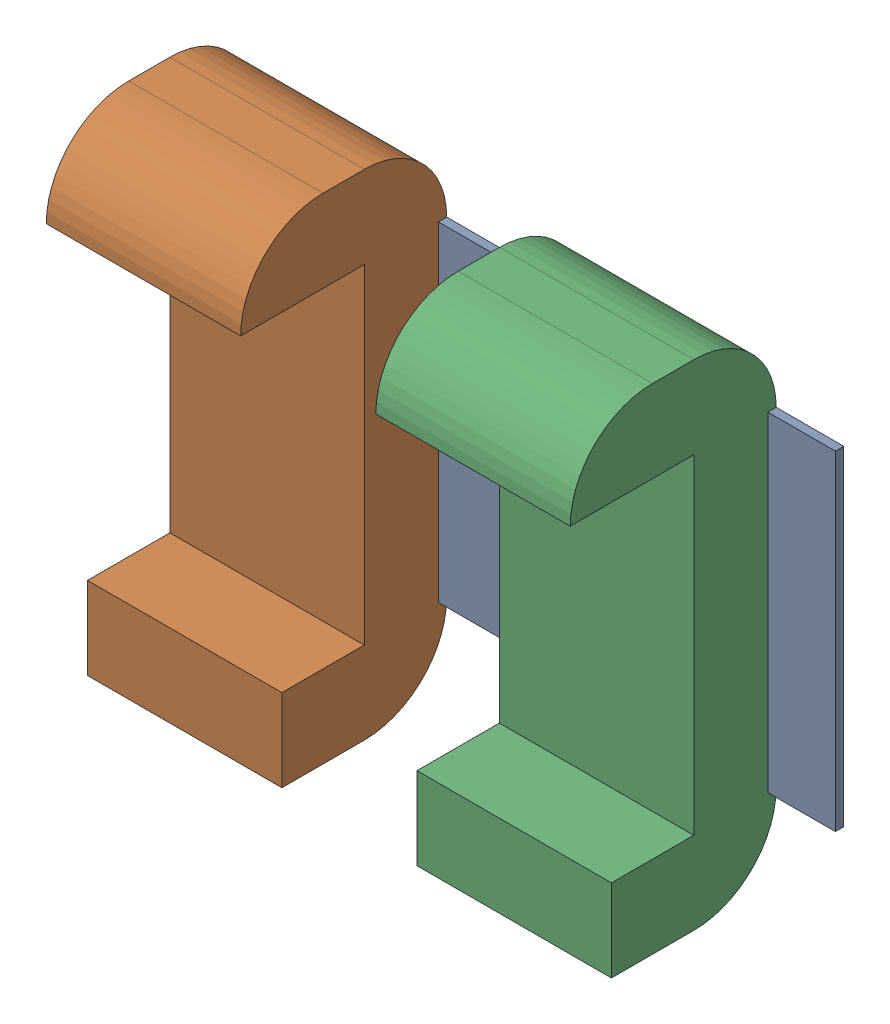
SolidWorks assembly JP1, configuration Predeterminado. Lengths in mm.
Overall size (2 1.5 0.63).
4 component instances, 3 part files, 0 mates.
Components (placement in the parent):
- Open CASCADE STEP translator 6.8 1.11.1-1: Open CASCADE STEP translator 6.8 1.11.1 [Predeterminado] at origin size (2 1.5 0.63)
  - Body_1_4-1: Body_1_4 [Predeterminado] at origin size (2 1 0.03)
  - Pin_1_3-1: Pin_1_3 [Predeterminado] x (0 1 0) z (0 0 1) size (1.5 0.59 0.63)
  - Pin_2_3-1: Pin_2_3 [Predeterminado] at (1 -1 0) x (0 1 0) z (0 0 1) size (1.5 0.59 0.63)
